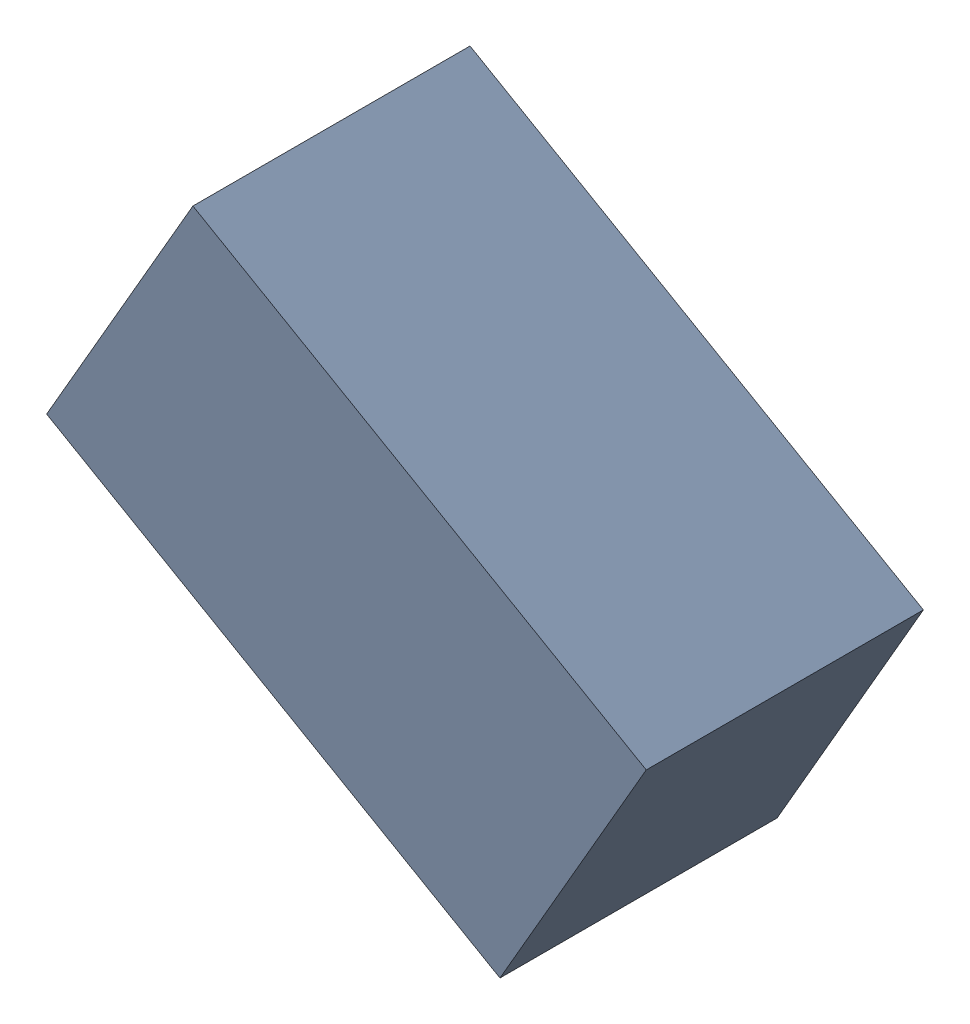
SolidWorks assembly R3_TDA6, configuration Standard. Lengths in mm.
Overall size (1.95 1.67 0.9).
2 component instances, 1 part files, 0 mates.
Components (placement in the parent):
- 885544144-1: 885544144 [Standard] at (-42.6285 32.8576 0) size (1.95 1.67 0.9)
  - Extruded_14-1: Extruded_14 [Standard] at origin size (1.95 1.67 0.9)
